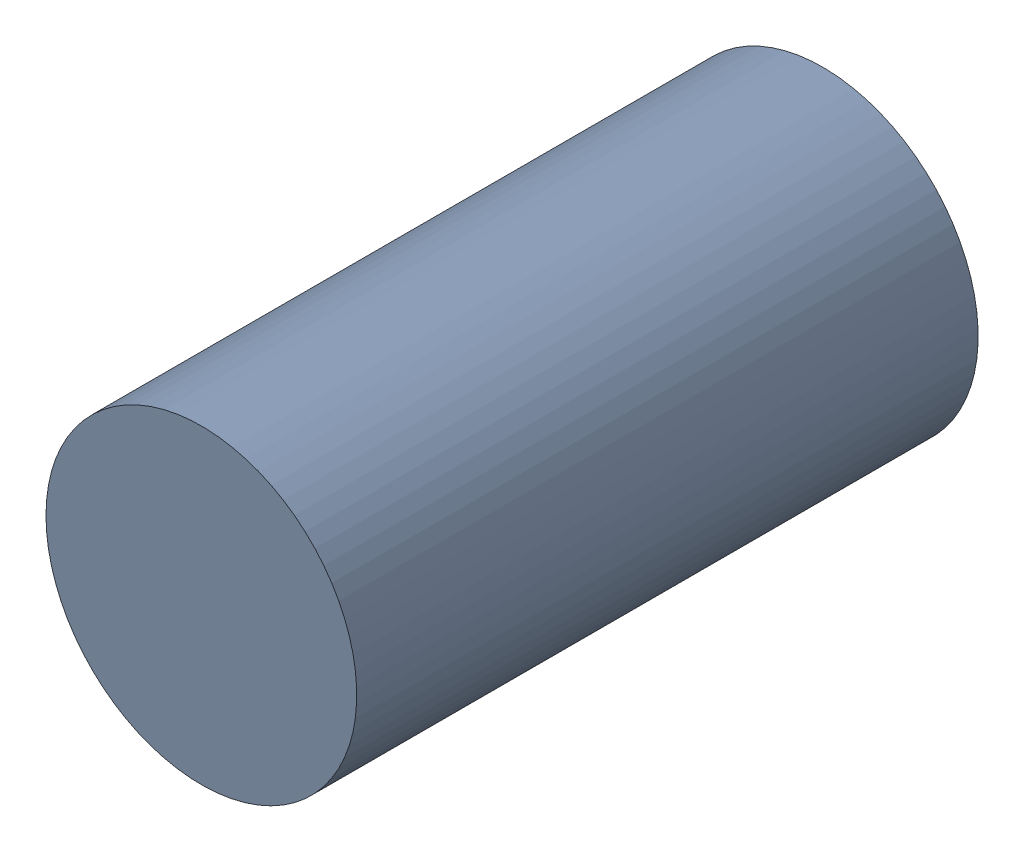
SolidWorks assembly MH8, configuration Default. Lengths in mm.
Overall size (1 1 2).
2 component instances, 1 part files, 0 mates.
Components (placement in the parent):
- 11929539264-1: 11929539264 [Default] at (142.3363 50.9276 -1.5) x (-1 0 0) z (0 0 1) size (1 1 2)
  - Cylinder-1: Cylinder [Default] at origin size (1 1 2)
